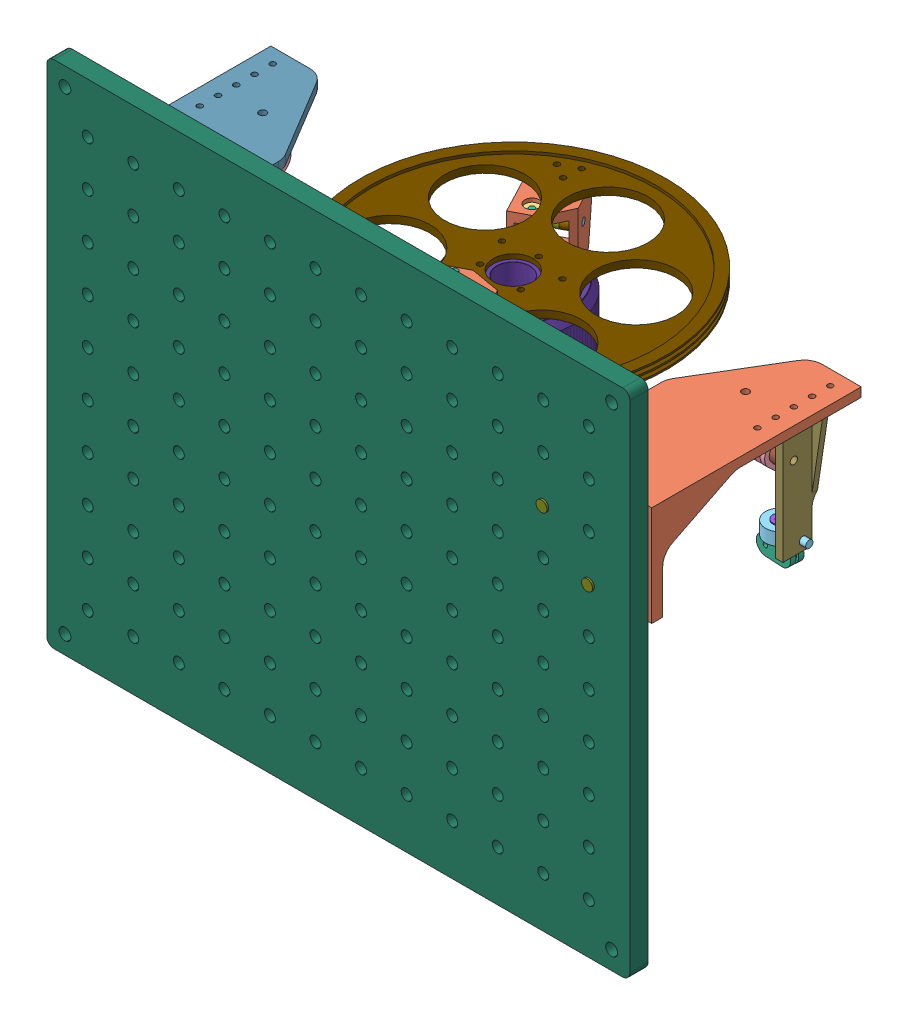
SolidWorks assembly 板套装3.0, configuration 默认. Lengths in mm.
Overall size (324 280 226.8).
61 component instances, 27 part files, 13 mates.
Components (placement in the parent):
- 拉力组件-1: 拉力组件 [默认] at (-26.825 -205.674 3032.0178) x (1 0 0) z (0 1 0) size (57 115 83.5) (flexible)
  - 拉力计-1: 拉力计 [Default] at (-50.9646 32.0178 -6) x (0 0 -1) z (0 1 0) size (25 11.8 30)
  - 六角柱与拉力机连接板-1: 六角柱与拉力机连接板 [默认] at (-69.3646 -2.9822 -25) size (57 115 55)
  - 拉力连接件-1: 拉力连接件 [默认] at (-56.8646 31.0178 -18.5) x (0 0 1) z (-1 0 0) size (10 20 18)
  - NT002滑轮-1: NT002滑轮 [默认] at (-61.8646 78.0178 -12) x (0.955567 0.294773 0) z (-0.294773 0.955567 0) size (15 8 35.78)
  - NT002滑轮-2: NT002滑轮 [默认] at (-58.3646 46.0178 -18.5) x (0 -0.861828 0.5072) z (0 0.5072 0.861828) size (15 8 35.78)
  - 万向绳-1: 万向绳 [默认] at (-52.8646 -5.1943 -42.9711) x (0 -1 0) z (1 0 0) size (16 18.5 26.37) (flexible)
    - 万向绳2-1: 万向绳2 [默认] at (-97.2122 22.5289 -4) size (16 7 24)
    - 万向绳1-1: 万向绳1 [默认] at (-93.4396 35.2789 0.5366) x (-0.058649 0 -0.998279) z (0 1 0) size (20 7 13.5)
    - 万向绳3-1: 万向绳3 [默认] at (-97.2122 27.0289 -4) size (11 2.5 11)
    - 万向绳4-1: 万向绳4 [默认] at (-97.2122 27.0289 -4) x (-0.837169 0 -0.546944) z (-0.546944 0 0.837169) size (8 5 8)
  - NT002滑轮-3: NT002滑轮 [默认] at (-58.3646 87.0178 -28.5) x (0 -0.853831 -0.520551) z (0 -0.520551 0.853831) size (15 8 35.78)
  - 拉力计滑轮垫片-1: 拉力计滑轮垫片 [默认] at (-60.8646 46.0178 -18.5) x (0 0.855913 0.51712) z (0 -0.51712 0.855913) size (10 2 10)
  - 滑轮1垫片-1: 滑轮1垫片 [默认] at (-61.8646 78.0178 -9.5) x (0.855913 -0.51712 0) z (-0.51712 -0.855913 0) size (10 4.5 10)
  - 滑轮2垫片-1: 滑轮2垫片 [默认] at (-52.8646 87.0178 -28.5) x (0 -0.855913 0.51712) z (0 0.51712 0.855913) size (10 4.5 10)
  - 拉力计滑轮垫片-2: 拉力计滑轮垫片 [默认] at (-50.8646 46.0178 -18.5) x (0 0.855913 0.51712) z (0 -0.51712 0.855913) size (10 2 10)
  - 滑轮2连接板2.0-2: 滑轮2连接板2.0 [默认] at (-41.3646 87.0178 -4) x (0 -1 0) z (1 0 0) size (19 70 10)
- 拉力组件右-1: 拉力组件右 [默认] at (-288.4864 -205.674 3034.2237) x (1 0 0) z (0 1 0) size (57 115 83.5) (flexible)
  - 拉力计-1: 拉力计 [Default] at (-64.3031 34.2237 -6) x (0 0 -1) z (0 1 0) size (25 11.8 30)
  - 拉力连接件-1: 拉力连接件 [默认] at (-70.2031 33.2237 -18.5) x (0 0 1) z (-1 0 0) size (10 20 18)
  - NT002滑轮-1: NT002滑轮 [默认] at (-65.2031 80.2237 -12) x (0.955567 0.294773 0) z (-0.294773 0.955567 0) size (15 8 35.78)
  - NT002滑轮-2: NT002滑轮 [默认] at (-71.7031 48.2237 -18.5) x (0 -0.861828 0.5072) z (0 0.5072 0.861828) size (15 8 35.78)
  - 万向绳-1: 万向绳 [默认] at (-74.0031 191.4358 -42.9711) x (0 1 0) z (-1 0 0) size (16 18.5 26.37) (flexible)
    - 万向绳2-1: 万向绳2 [默认] at (-97.2122 22.5289 -4) size (16 7 24)
    - 万向绳1-1: 万向绳1 [默认] at (-92.1831 35.2789 -0.9144) x (-0.375978 0 -0.926629) z (0 1 0) size (20 7 13.5)
    - 万向绳3-1: 万向绳3 [默认] at (-97.2122 27.0289 -4) size (11 2.5 11)
    - 万向绳4-1: 万向绳4 [默认] at (-97.2122 27.0289 -4) x (-0.837169 0 -0.546944) z (-0.546944 0 0.837169) size (8 5 8)
  - NT002滑轮-3: NT002滑轮 [默认] at (-68.7031 89.2237 -28.5) x (0 0.495502 -0.868607) z (0 0.868607 0.495502) size (15 8 35.78)
  - 拉力计滑轮垫片-1: 拉力计滑轮垫片 [默认] at (-74.2031 48.2237 -18.5) x (0 0.855913 0.51712) z (0 -0.51712 0.855913) size (10 2 10)
  - 滑轮1垫片-1: 滑轮1垫片 [默认] at (-65.2031 80.2237 -9.5) x (0.855913 -0.51712 0) z (-0.51712 -0.855913 0) size (10 4.5 10)
  - 滑轮2连接板2.0右-1: 滑轮2连接板2.0右 [默认] at (-85.7031 89.2237 -4) x (0 1 0) z (-1 0 0) size (19 70 10)
  - 滑轮2垫片-1: 滑轮2垫片 [默认] at (-74.2031 89.2237 -28.5) x (0 0.855913 0.51712) z (0 -0.51712 0.855913) size (10 4.5 10)
  - 拉力计滑轮垫片-2: 拉力计滑轮垫片 [默认] at (-64.2031 48.2237 -18.5) x (0 0.855913 0.51712) z (0 -0.51712 0.855913) size (10 2 10)
  - 六角柱与拉力机连接板右-2: 六角柱与拉力机连接板右 [默认] at (-82.7031 -0.7763 -25) size (57 115 55)
- 定位板-1: 定位板 [默认] at (-221.1895 -286.674 3035) x (1 0 0) z (0 -1 0) size (320 10 280)
- 塞打螺丝M6_5-1: 塞打螺丝M6_5 [默认] at (-83.6895 -249.174 3023.5) x (-0.923728 -0.383049 0) z (-0.383049 0.923728 0) size (13 22.5 13)
- 塞打螺丝M6_5-6: 塞打螺丝M6_5 [默认] at (-108.6895 -224.174 3023.5) x (-0.85131 -0.524663 0) z (-0.524663 0.85131 0) size (13 22.5 13)
- 电机固定组件3.0-1: 电机固定组件3.0 [默认] at (-71.1895 -262.6144 2965.7798) x (0 1 0) z (-1 0 0) size (127 226.8 226.8)
  - RoboMaster GM6020 直流无刷电机-1: RoboMaster GM6020 直流无刷电机 [默认] at (116.9883 16.7798 150) x (0 -0.866025 -0.5) z (1 0 0) size (66.7 66.7 45)
  - 轮组2.0-1: 轮组2.0 [默认] at (40.4404 16.7798 150) x (0 0.885679 0.464298) z (0 0.464298 -0.885679) size (168 7.5 168)
  - 电机固定3.0-1: 电机固定3.0 [默认] at (-49.0596 -69.2202 115) size (75 137.5 86)
  - 装配体-1: 装配体 [默认] at (62.4555 -53.5546 154.7908) x (1 0 0) z (0 0.464298 -0.885679) size (32 33.9 26)
    - box - 0-1: box - 0 [默认] at (-1.5151 4.9306 23.8992) size (28 33.9 26)
    - bearing-1: bearing [默认] at (-12.3151 -9.9694 28.8992) x (0 0 1) z (-1 0 0) size (9 9 3)
    - bearing-2: bearing [默认] at (9.2849 -9.9694 28.8992) x (0 -0.428044 -0.903758) z (1 0 0) size (9 9 3)
    - 零件2-1: 零件2 [默认] at (-11.5151 -9.9694 28.8992) x (1 0 0) z (0 -0.101118 0.994874) size (20 9.82 9.8)
    - zhou1-1: zhou1 [默认] at (-5.5151 -0.5694 20.8992) x (1 0 0) z (0 -1 0) size (4 26 4)
    - zhou2-1: zhou2 [默认] at (-14.5151 -9.9694 28.8992) x (0 0 -1) z (1 0 0) size (3 3 30)
    - gear-1: gear [默认] at (-5.5151 -0.5694 31.3992) x (0 0 -1) z (0.913862 -0.406024 0) size (12 10.93 10.93)
    - 1-1: 1 [默认] at (-5.5151 -0.5694 23.8992) x (0.998523 -0.054325 0) z (0 0 1) size (9 9 2.5)
    - 2-1: 2 [默认] at (-5.5151 -0.5694 38.3992) x (0.999989 0.004731 0) z (0 0 1) size (9 9 5.5)
  - 装配体-2: 装配体 [默认] at (25.4254 52.8498 210.571) x (-1 0 0) z (0 0.464298 -0.885679) size (32 33.9 26)
    - box - 0-1: box - 0 [默认] at (-1.5151 4.9306 23.8992) size (28 33.9 26)
    - bearing-1: bearing [默认] at (-12.3151 -9.9694 28.8992) x (0 0 1) z (-1 0 0) size (9 9 3)
    - bearing-2: bearing [默认] at (9.2849 -9.9694 28.8992) x (0 -0.428044 -0.903758) z (1 0 0) size (9 9 3)
    - 零件2-1: 零件2 [默认] at (-11.5151 -9.9694 28.8992) x (1 0 0) z (0 -0.101118 0.994874) size (20 9.82 9.8)
    - zhou1-1: zhou1 [默认] at (-5.5151 -0.5694 20.8992) x (1 0 0) z (0 -1 0) size (4 26 4)
    - zhou2-1: zhou2 [默认] at (-14.5151 -9.9694 28.8992) x (0 0 -1) z (1 0 0) size (3 3 30)
    - gear-1: gear [默认] at (-5.5151 -0.5694 31.3992) x (0 0 -1) z (0.913862 -0.406024 0) size (12 10.93 10.93)
    - 1-1: 1 [默认] at (-5.5151 -0.5694 23.8992) x (0.998523 -0.054325 0) z (0 0 1) size (9 9 2.5)
    - 2-1: 2 [默认] at (-5.5151 -0.5694 38.3992) x (0.999989 0.004731 0) z (0 0 1) size (9 9 5.5)
Mates (geometry in assembly coordinates):
- 重合2: coincident anti-aligned: plane of 拉力组件-1/六角柱与拉力机连接板-1 through (-96.1895 -230.674 3035) normal (0 0 1); plane of 定位板-1 through (-221.1895 -286.674 3035) normal (0 0 -1)
- 重合4: coincident anti-aligned: plane of 拉力组件右-1/六角柱与拉力机连接板右-2 through (-371.1895 -230.674 3035) normal (0 0 1); plane of 定位板-1 through (-221.1895 -286.674 3035) normal (0 0 -1)
- 同心3: concentric anti-aligned: circle of 拉力组件-1/六角柱与拉力机连接板-1; circle of 定位板-1
- 同心4: concentric anti-aligned: circle of 拉力组件-1/六角柱与拉力机连接板-1; circle of 定位板-1
- 重合7: coincident anti-aligned: plane of 拉力组件-1/六角柱与拉力机连接板-1 through (-96.1895 -230.674 3029) normal (0 0 -1); plane of 塞打螺丝M6_5-1 through (-83.6895 -249.174 3029) normal (0 0 1)
- 同心7: concentric anti-aligned: circle of 塞打螺丝M6_5-1; circle of 拉力组件-1/六角柱与拉力机连接板-1
- 重合10: coincident anti-aligned: plane of 拉力组件-1/六角柱与拉力机连接板-1 through (-96.1895 -230.674 3029) normal (0 0 -1); plane of 塞打螺丝M6_5-6 through (-108.6895 -224.174 3029) normal (0 0 1)
- 同心9: concentric anti-aligned: circle of 拉力组件-1/六角柱与拉力机连接板-1; circle of 塞打螺丝M6_5-6
- 重合13: coincident anti-aligned: plane of 定位板-1 through (-221.1895 -286.674 3035) normal (0 0 -1); plane of 电机固定组件3.0-1/电机固定3.0-1 through (-186.1895 -311.674 3035) normal (0 0 1)
- 同心12: concentric aligned: circle of 定位板-1; circle of 电机固定组件3.0-1/电机固定3.0-1
- 同心13: concentric aligned: circle of 定位板-1; circle of 电机固定组件3.0-1/电机固定3.0-1
- 同心14: concentric anti-aligned: circle of 拉力组件右-1/六角柱与拉力机连接板右-2; circle of 定位板-1
- 同心15: concentric anti-aligned: circle of 拉力组件右-1/六角柱与拉力机连接板右-2; circle of 定位板-1
